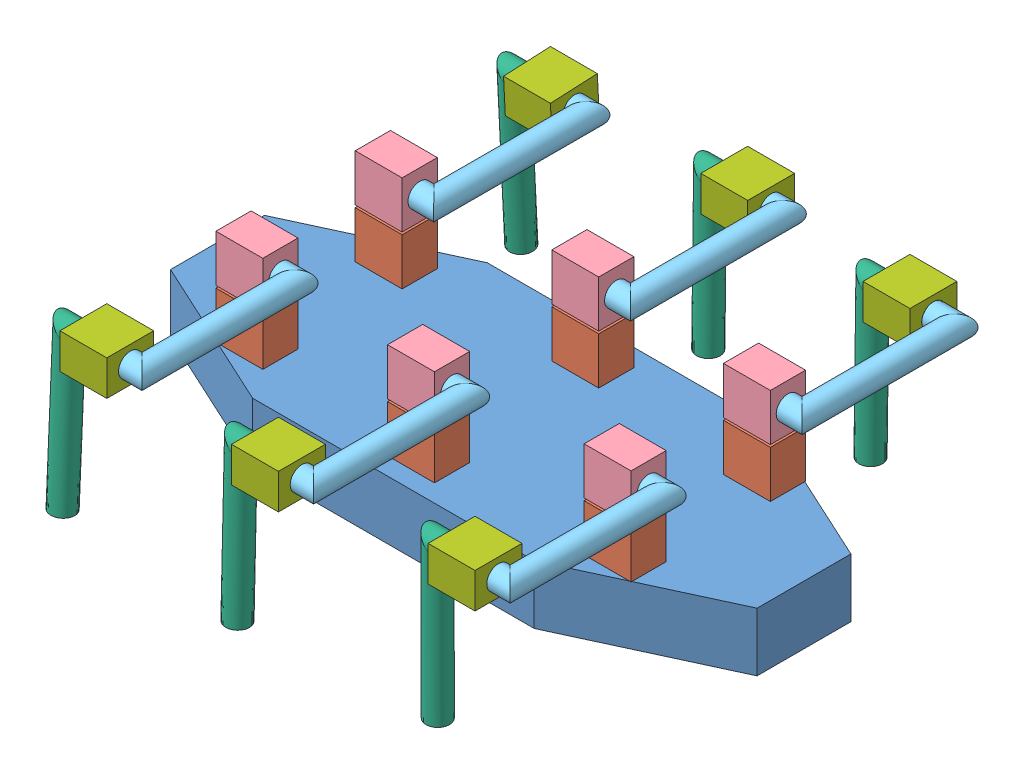
SolidWorks assembly Assem, configuration Default. Lengths in mm.
Overall size (256.94 105.17 220).
37 component instances, 7 part files, 70 mates.
Components (placement in the parent):
- Part2-1: Part2 [Default] at origin size (250 25 100)
- Part5-1: Part5 [Default] at (10 35 35) x (0 1 0) z (0 0 1) size (20 20 15)
- Part6-1: Part6 [Default] at (0 35 35) x (-0.99817 0 0.060477) z (-0.060477 0 -0.99817) size (10 15 10)
- Part5-2: Part5 [Default] at (-68.4707 35 -29.6916) x (0 1 0) z (0 0 1) size (20 20 15)
- Part6-2: Part6 [Default] at (-78.4707 35 29.6916) x (-0.240518 0 -0.970645) z (0.970645 0 -0.240518) size (10 15 10)
- Part5-3: Part5 [Default] at (68.4707 35 29.6916) x (0 1 0) z (0 0 -1) size (20 20 15)
- Part6-3: Part6 [Default] at (-78.4707 35 -29.6916) x (-0.920824 0 -0.389979) z (0.389979 0 -0.920824) size (10 15 10)
- Part6-4: Part6 [Default] at (78.4707 50 29.6916) x (-0.837169 0 -0.546944) z (-0.546944 0 0.837169) size (10 15 10)
- Part6-5: Part6 [Default] at (0 50 -35) x (-0.997994 0 -0.063309) z (-0.063309 0 0.997994) size (10 15 10)
- Part5-4: Part5 [Default] at (-68.4707 35 29.6916) x (0 1 0) z (0 0 1) size (20 20 15)
- Part5-5: Part5 [Default] at (10 35 -35) x (0 1 0) z (0 0 1) size (20 20 15)
- Part5-6: Part5 [Default] at (68.4707 35 -29.6916) x (0 1 0) z (0 0 -1) size (20 20 15)
- Part6-6: Part6 [Default] at (78.4707 50 -29.6916) x (-0.889881 0 0.456193) z (0.456193 0 0.889881) size (10 15 10)
- Part5 - Copy-1: Part5 - Copy [Default] at (78.4707 46 -29.6916) size (20 20 15)
- Part7-1: Part7 [Default] at (78.4707 56 -29.6916) x (0 -1 0) z (0 0 1) size (10 21 75)
- feet-1: feet [Default] at (75.4707 56 -94.6916) x (0 -0.01256 -0.999921) z (0 0.999921 -0.01256) size (10 21 70)
- foot-servo-1: foot-servo [Default] at (75.4707 56 -84.6916) x (-1 0 0) z (0 -1 0) size (20 20 15)
- foot-servo-2: foot-servo [Default] at (1 56 -90) x (-1 0 0) z (0 -1 0) size (20 20 15)
- Part5 - Copy-2: Part5 - Copy [Default] at (0 46 -35) size (20 20 15)
- feet-2: feet [Default] at (1 56 -100) x (0 -0.012359 -0.999924) z (0 0.999924 -0.012359) size (10 21 70)
- Part7-2: Part7 [Default] at (0 56 -35) x (0 -1 0) z (0 0 1) size (10 21 75)
- feet-3: feet [Default] at (-77.3868 56 -94.6903) x (0.001289 0.04907 -0.998795) z (-0.000063 0.998795 0.04907) size (10 21 70)
- foot-servo-3: foot-servo [Default] at (-77.3997 55.5038 -84.7026) x (-0.999999 0 -0.001291) z (0.000064 -0.998768 -0.049623) size (20 20 15)
- Part5 - Copy-3: Part5 - Copy [Default] at (-78.4707 46 -29.6916) x (0.999999 0 0.001291) z (-0.001291 0 0.999999) size (20 20 15)
- Part7-3: Part7 [Default] at (-78.4707 56 -29.6916) x (0 -1 0) z (-0.001291 0 0.999999) size (10 21 75)
- foot-servo-4: foot-servo [Default] at (79.4707 56 104.6916) x (-1 0 0) z (0 -1 0) size (20 20 15)
- Part7-4: Part7 [Default] at (-78.4707 56 29.6916) x (0 1 0) z (0 0 -1) size (10 21 75)
- Part5 - Copy-4: Part5 - Copy [Default] at (78.4707 46 29.6916) size (20 20 15)
- Part7-5: Part7 [Default] at (78.4707 56 29.6916) x (0 1 0) z (0 0 -1) size (10 21 75)
- feet-4: feet [Default] at (79.4707 56 94.6916) x (0 0.001949 -0.999998) z (0 0.999998 0.001949) size (10 21 70)
- feet-5: feet [Default] at (-77.4707 56 94.6916) x (0 -0.04379 -0.999041) z (0 0.999041 -0.04379) size (10 21 70)
- foot-servo-5: foot-servo [Default] at (-77.4707 56 104.6916) x (-1 0 0) z (0 -1 0) size (20 20 15)
- foot-servo-6: foot-servo [Default] at (1 56 110) x (-1 0 0) z (0 -1 0) size (20 20 15)
- Part7-6: Part7 [Default] at (0 56 35) x (0 1 0) z (0 0 -1) size (10 21 75)
- feet-6: feet [Default] at (1 56 100) x (0 -0.022746 -0.999741) z (0 0.999741 -0.022746) size (10 21 70)
- Part5 - Copy-5: Part5 - Copy [Default] at (-78.4707 46 29.6916) size (20 20 15)
- Part5 - Copy-6: Part5 - Copy [Default] at (0 46 35) size (20 20 15)
Mates (geometry in assembly coordinates):
- Concentric1: concentric anti-aligned: circle of Part2-1; circle of Part5-1
- Coincident4: coincident anti-aligned: plane of Part2-1 through (0 25 0) normal (0 1 0); plane of Part5-1 through (-10 25 27.5) normal (0 -1 0)
- Parallel2: parallel anti-aligned: line of Part2-1 through (60 25 50) axis (-1 0 0); line of Part5-1 through (-10 25 42.5) axis (1 0 0)
- Concentric2: concentric anti-aligned: cylinder of Part5-1 through (0 35 35) axis (0 1 0) radius 5; cylinder of Part6-1 through (0 50 35) axis (0 -1 0) radius 5
- Coincident6: coincident aligned: circle of Part5-1; circle of Part6-1
- Concentric4: concentric anti-aligned: circle of Part2-1; circle of Part5-4
- Coincident9: coincident anti-aligned: plane of Part2-1 through (0 25 0) normal (0 1 0); plane of Part5-4 through (-88.4707 25 22.1916) normal (0 -1 0)
- Parallel4: parallel anti-aligned: line of Part2-1 through (60 25 50) axis (-1 0 0); line of Part5-4 through (-88.4707 25 37.1916) axis (1 0 0)
- Coincident11: coincident aligned: circle of Part6-2; circle of Part5-4
- Concentric6: concentric anti-aligned: cylinder of Part6-2 through (-78.4707 50 29.6916) axis (0 -1 0) radius 5; cylinder of Part5-4 through (-78.4707 35 29.6916) axis (0 1 0) radius 5
- Concentric9: concentric anti-aligned: circle of Part2-1; circle of Part5-2
- Coincident14: coincident anti-aligned: plane of Part2-1 through (0 25 0) normal (0 1 0); plane of Part5-2 through (-88.4707 25 -37.1916) normal (0 -1 0)
- Parallel6: parallel aligned: line of Part2-1 through (-60 25 -50) axis (1 0 0); line of Part5-2 through (-88.4707 25 -37.1916) axis (1 0 0)
- Coincident18: coincident aligned: circle of Part5-2; circle of Part6-3
- Concentric10: concentric anti-aligned: circle of Part2-1; circle of Part5-5
- Coincident19: coincident anti-aligned: plane of Part2-1 through (0 25 0) normal (0 1 0); plane of Part5-5 through (-10 25 -42.5) normal (0 -1 0)
- Coincident20: coincident anti-aligned: circle of Part6-5; circle of Part5-5
- Concentric11: concentric anti-aligned: circle of Part2-1; circle of Part5-3
- Coincident21: coincident anti-aligned: plane of Part2-1 through (0 25 0) normal (0 1 0); plane of Part5-3 through (88.4707 25 37.1916) normal (0 -1 0)
- Coincident22: coincident anti-aligned: circle of Part5-3; circle of Part6-4
- Concentric12: concentric anti-aligned: circle of Part2-1; circle of Part5-6
- Coincident23: coincident anti-aligned: plane of Part2-1 through (0 25 0) normal (0 1 0); plane of Part5-6 through (88.4707 25 -22.1916) normal (0 -1 0)
- Coincident24: coincident anti-aligned: circle of Part5-6; circle of Part6-6
- Parallel7: parallel anti-aligned: line of Part2-1 through (60 25 50) axis (-1 0 0); line of Part5-4 through (-88.4707 25 37.1916) axis (1 0 0)
- Parallel8: parallel aligned: line of Part2-1 through (60 25 50) axis (-1 0 0); line of Part5-3 through (88.4707 25 37.1916) axis (-1 0 0)
- Parallel9: parallel anti-aligned: line of Part2-1 through (-60 25 -50) axis (1 0 0); line of Part5-6 through (88.4707 25 -22.1916) axis (-1 0 0)
- Parallel10: parallel aligned: line of Part2-1 through (-60 25 -50) axis (1 0 0); line of Part5-5 through (-10 25 -42.5) axis (1 0 0)
- Coincident28: coincident aligned: circle of Part6-6; circle of Part5 - Copy-1
- Coincident30: coincident aligned: circle of Part5 - Copy-1; circle of Part7-1
- Coincident31: coincident anti-aligned: circle of Part7-1; circle of foot-servo-1
- Coincident32: coincident aligned: circle of feet-1; circle of foot-servo-1
- Coincident33: coincident aligned: circle of Part6-5; circle of Part5 - Copy-2
- Coincident34: coincident aligned: circle of Part5 - Copy-2; circle of Part7-2
- Coincident35: coincident anti-aligned: circle of foot-servo-2; circle of Part7-2
- Coincident37: coincident aligned: plane of foot-servo-2 through (1 56 -100) normal (-1 0 0); circle of feet-2
- Concentric13: concentric aligned: cylinder of foot-servo-2 through (1 56 -100) axis (-1 0 0) radius 5; cylinder of feet-2 through (1 56 -100) axis (-1 0 0) radius 5
- Coincident38: coincident anti-aligned: circle of Part6-3; circle of Part5 - Copy-3
- Coincident39: coincident aligned: circle of Part5 - Copy-3; circle of Part7-3
- Coincident40: coincident anti-aligned: circle of foot-servo-3; circle of Part7-3
- Coincident41: coincident aligned: circle of feet-3; circle of foot-servo-3
- Coincident42: coincident aligned: circle of Part6-4; circle of Part5 - Copy-4
- Coincident43: coincident aligned: circle of Part5 - Copy-4; circle of Part7-5
- Coincident44: coincident anti-aligned: circle of foot-servo-4; circle of Part7-5
- Coincident45: coincident aligned: circle of foot-servo-4; circle of feet-4
- Coincident46: coincident anti-aligned: circle of Part6-1; circle of Part5 - Copy-6
- Coincident47: coincident aligned: circle of Part7-6; circle of Part5 - Copy-6
- Coincident48: coincident anti-aligned: circle of Part6-2; circle of Part5 - Copy-5
- Coincident49: coincident aligned: circle of Part7-4; circle of Part5 - Copy-5
- Coincident50: coincident anti-aligned: circle of foot-servo-6; circle of Part7-6
- Coincident51: coincident aligned: circle of foot-servo-6; circle of feet-6
- Coincident52: coincident anti-aligned: circle of Part7-4; circle of foot-servo-5
- Coincident53: coincident aligned: circle of feet-5; circle of foot-servo-5
- LimitAngle1: limit planar angle = 0.001291 rad aligned: plane of Part5 - Copy-3 through (-88.461 66 -37.2045) normal (0.001291 0 -0.999999); plane of Part5-2 through (-88.4707 25 -37.1916) normal (0 0 -1)
- LimitAngle2: limit planar angle = 0 rad aligned: plane of Part5 - Copy-2 through (-10 66 -42.5) normal (0 0 -1); plane of Part5-5 through (-10 25 -42.5) normal (0 0 -1)
- LimitAngle3: limit planar angle = 0 rad aligned: plane of Part5 - Copy-1 through (68.4707 66 -37.1916) normal (0 0 -1); plane of Part5-6 through (88.4707 25 -37.1916) normal (0 0 -1)
- LimitAngle4: limit planar angle = 0 rad aligned: plane of Part5 - Copy-4 through (68.4707 66 37.1916) normal (0 0 1); plane of Part5-3 through (88.4707 25 37.1916) normal (0 0 1)
- LimitAngle5: limit planar angle = 0 rad aligned: plane of Part5 - Copy-6 through (-10 66 42.5) normal (0 0 1); plane of Part5-1 through (-10 25 42.5) normal (0 0 1)
- LimitAngle6: limit planar angle = 0 rad aligned: plane of Part5 - Copy-5 through (-88.4707 66 37.1916) normal (0 0 1); plane of Part5-4 through (-88.4707 25 37.1916) normal (0 0 1)
- LimitAngle8: limit planar angle = 1.570796 rad aligned: cylinder of feet-5 through (-93.4707 61.5946 94.4464) axis (0 -0.999041 0.04379) radius 5
- LimitAngle9: limit planar angle = 1.570796 rad aligned: cylinder of feet-6 through (-15 61.5986 99.8726) axis (0 -0.999741 0.022746) radius 5
- LimitAngle10: limit planar angle = 1.570796 rad anti-aligned: cylinder of feet-4 through (63.4707 61.6 94.7025) axis (0 -0.999998 -0.001949) radius 5
- LimitAngle11: limit planar angle = 1.570796 rad aligned: cylinder of feet-1 through (59.4707 61.5996 -94.762) axis (0 -0.999921 0.01256) radius 5
- LimitAngle12: limit planar angle = 1.570796 rad aligned: cylinder of feet-2 through (-15 61.5996 -100.0692) axis (0 -0.999924 0.012359) radius 5
- LimitAngle13: limit planar angle = 1.570796 rad aligned: cylinder of feet-3 through (-93.3871 61.5933 -94.4361) axis (0.000063 -0.998795 -0.04907) radius 5
- LimitAngle14: limit planar angle = 1.570796 rad anti-aligned: cylinder of Part7-4 through (-62.4707 56 24.0916) axis (0 0 1) radius 5
- LimitAngle15: limit planar angle = 1.570796 rad aligned: cylinder of Part7-6 through (16 56 29.4) axis (0 0 1) radius 5
- LimitAngle16: limit planar angle = 1.570796 rad anti-aligned: cylinder of Part7-5 through (94.4707 56 24.0916) axis (0 0 1) radius 5
- LimitAngle17: limit planar angle = 1.570796 rad aligned: cylinder of Part7-1 through (94.4707 56 -24.0916) axis (0 0 -1) radius 5
- LimitAngle18: limit planar angle = 1.570796 rad anti-aligned: cylinder of Part7-2 through (16 56 -29.4) axis (0 0 -1) radius 5
- LimitAngle19: limit planar angle = 1.570796 rad aligned: cylinder of Part7-3 through (-62.4779 56 -24.071) axis (0.001291 0 -0.999999) radius 5
